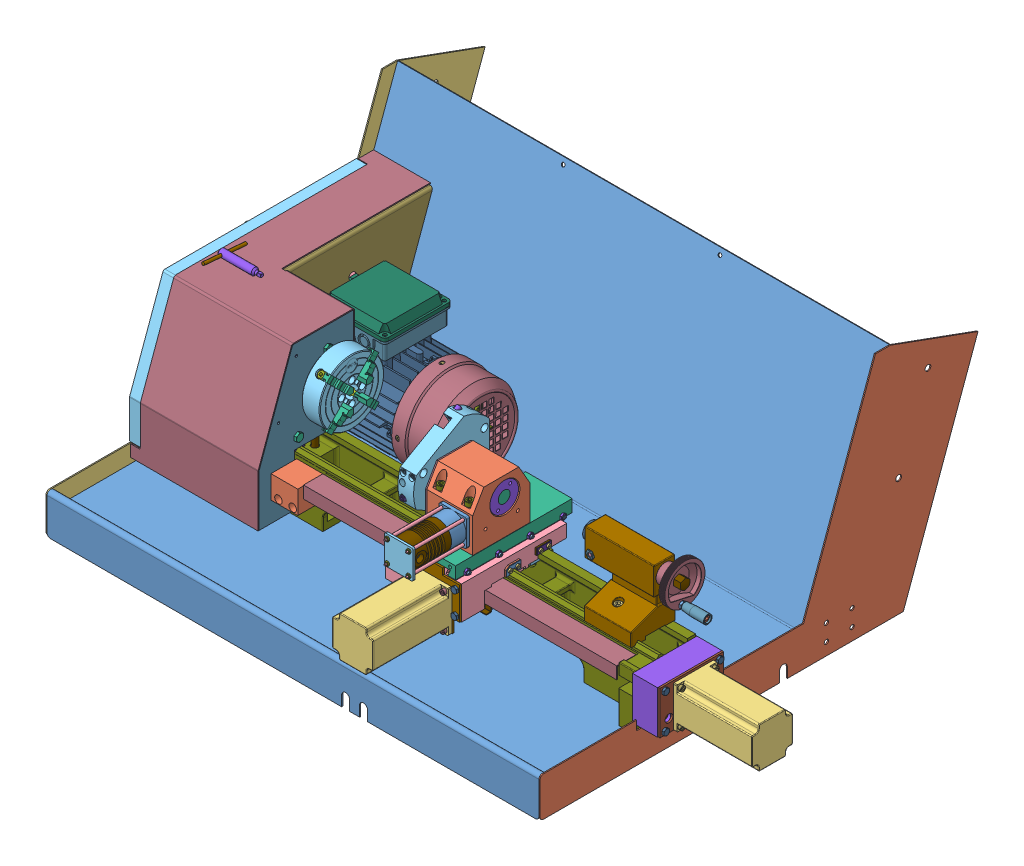
SolidWorks assembly Emco Compact 5 CNC, configuration Default. Lengths in mm.
Overall size (835.1 331.1 618.32).
327 component instances, 165 part files, 0 mates.
Components (placement in the parent):
- Emco Compact 5 CNC.stp-1: Emco Compact 5 CNC.stp [Default] at origin size (835.1 331.1 618.32)
  - A6A 060 001 chiptray.stp-1: A6A 060 001 chiptray.stp [Default] at origin size (690 331.1 611.82)
    - A6A 060 001 chiptray bottom part.stp-1: A6A 060 001 chiptray bottom part.stp [Default] at origin size (687 331.09 491)
    - A6A 060 001 chiptray right part.stp-1: A6A 060 001 chiptray right part.stp [Default] at (687 0 0) size (1.5 331.1 611.82)
    - A6A 060 001 chiptray left part.stp-1: A6A 060 001 chiptray left part.stp [Default] at (-1.5 0 0) size (1.5 331.1 611.82)
  - A6A 050 000 cover.stp-1: A6A 050 000 cover.stp [Default] at (0 55 -366.75) x (0 0 1) z (-1 0 0) size (316.79 204.5 24)
    - A6A 050 000 cover side.stp-1: A6A 050 000 cover side.stp [Default] at origin size (315.29 182 15)
    - A6A 050 000 cover strip.stp-1: A6A 050 000 cover strip.stp [Default] at (0 0 -13.5) size (316.79 183.5 15)
    - ZSR 12 0620 M6x20 Socket head screw.stp-1: ZSR 12 0620 M6x20 Socket head screw.stp [Default] at (82 176 3.1) x (0 0 -1) z (1 0 0) size (24 10 10)
    - ZSB 25 0640 M6 washer.stp-1: ZSB 25 0640 M6 washer.stp [Default] at (82 176 1.5) x (0 0 1) z (-1 0 0) size (1.6 12 12)
    - ZSB 25 0640 M6 washer.stp-2: ZSB 25 0640 M6 washer.stp [Default] at (82 176 -1.6) x (0 0 1) z (-1 0 0) size (1.6 12 12)
    - ZRG 71 0607 6mm retaining ring.stp-1: ZRG 71 0607 6mm retaining ring.stp [Default] at (82 173 -2.6) x (1 0 0) z (0 0 -1) size (7.95 9.79 0.7)
    - A6A 050 000 cover hinge_1.stp-1: A6A 050 000 cover hinge_1.stp [Default] at (233 0.5 1.5) x (0 -1 0) z (-1 0 0) size (23 6 44)
    - A6A 050 000 cover hinge_2.stp-1: A6A 050 000 cover hinge_2.stp [Default] at (189 0.5 1.5) x (0 1 0) z (1 0 0) size (23 6 44)
    - A6A 050 000 cover hinge shaft.stp-1: A6A 050 000 cover hinge shaft.stp [Default] at (189 0.5 1.5) x (0 0.845481 0.534005) z (1 0 0) size (3 3 44)
    - A6A 050 000 cover hinge_1.stp-2: A6A 050 000 cover hinge_1.stp [Default] at (53 0.5 1.5) x (0 -1 0) z (-1 0 0) size (23 6 44)
    - A6A 050 000 cover hinge_2.stp-2: A6A 050 000 cover hinge_2.stp [Default] at (9 0.5 1.5) x (0 1 0) z (1 0 0) size (23 6 44)
    - A6A 050 000 cover hinge shaft.stp-2: A6A 050 000 cover hinge shaft.stp [Default] at (9 0.5 1.5) x (0 0.845481 0.534005) z (1 0 0) size (3 3 44)
  - A6A 030 000 Headstock cover.stp-1: A6A 030 000 Headstock cover.stp [Default] at (66.5 30 -468.25) x (0 0 1) z (-1 0 0) size (339.29 210 178.5)
    - A6A 030 000 Headstock cover - Motorplate.stp-1: A6A 030 000 Headstock cover - Motorplate.stp [Default] at origin size (335.89 208.5 18.5)
    - A6A 030 000 Headstock cover - Topplate.stp-1: A6A 030 000 Headstock cover - Topplate.stp [Default] at (101.4998 25 -111.5) size (339.29 202.5 178.5)
    - A6A 030 000 Headstock cover - Spindleplate.stp-1: A6A 030 000 Headstock cover - Spindleplate.stp [Default] at (350 7.5 -110) x (0 0 -1) z (1 0 0) size (1.5 201 132)
    - A6A 030 000 Headstock cover - lock.stp-1: A6A 030 000 Headstock cover - lock.stp [Default] at (176.2113 208.5 35.5) x (0 0 1) z (1 0 0) size (21 13.5 12)
  - Bed complete.stp-1: Bed complete.stp [Default] at (86.5 30 -140.9) size (821.5 208.51 283.01)
    - Bed with head and tailstock.stp-1: Bed with head and tailstock.stp [Default] at origin size (594 187 111.85)
      - A6A 010 010 Bed.stp-1: A6A 010 010 Bed.stp [Default] at origin size (594 80 90)
      - A5A 010 020 Headstock.stp-1: A5A 010 020 Headstock.stp [Default] at (0 76.4996 -25.1) x (0 0 -1) z (1 0 0) size (80 110.5 90)
      - DIN 912 - M8 x 1,25 x 45 x 28.stp-1: DIN 912 - M8 x 1,25 x 45 x 28.stp [Default] at (17.5 50.5 -53.25) x (0 1 0) z (0 0 -1) size (53 13 13)
      - DIN 912 - M8 x 1,25 x 45 x 28.stp-2: DIN 912 - M8 x 1,25 x 45 x 28.stp [Default] at (80 50.5 -66.75) x (0 1 0) z (0 0 1) size (53 13 13)
      - DIN 912 - M8 x 1,25 x 45 x 28.stp-3: DIN 912 - M8 x 1,25 x 45 x 28.stp [Default] at (80 50.5 -45.25) x (0 1 0) z (0 0 1) size (53 13 13)
      - DIN 127 - A 8.stp-1: DIN 127 - A 8.stp [Default] at (80 52.5 -45.25) x (0 -1 0) z (0 0 -1) size (2 14.8 14.8)
      - DIN 127 - A 8.stp-2: DIN 127 - A 8.stp [Default] at (80 52.5 -66.75) x (0 -1 0) z (0 0 -1) size (2 14.8 14.8)
      - DIN 127 - A 8.stp-3: DIN 127 - A 8.stp [Default] at (17.5 52.5 -53.25) x (0 -1 0) z (0 0 1) size (2 14.8 14.8)
      - A6A 000 040 Bearing block.stp-1: A6A 000 040 Bearing block.stp [Default] at (92 36.5 -29.25) size (37.5 32 36)
      - DIN 912 - M5 x 0,8 x 30 x 22.stp-1: DIN 912 - M5 x 0,8 x 30 x 22.stp [Default] at (122.5 42.5 -5.25) x (0 0 -1) z (0 1 0) size (35 8.5 8.5)
      - DIN 912 - M5 x 0,8 x 30 x 22.stp-2: DIN 912 - M5 x 0,8 x 30 x 22.stp [Default] at (102.5 42.5 -5.25) x (0 0 -1) z (0 1 0) size (35 8.5 8.5)
      - eBom-prt21.stp-1: eBom-prt21.stp [Default] at origin
    - Mainspindle pulley.stp-1: Mainspindle pulley.stp [Default] at (-41.5 144.9996 -72.1) size (41.5 127.02 127.02)
      - A6A 000 020 pulley.stp-1: A6A 000 020 pulley.stp [Default] at (41 0 0) x (0 0.866396 -0.499357) z (0 0.499357 0.866396) size (93 41 93)
      - A6A 000 110 Dividing washer 100.stp-1: A6A 000 110 Dividing washer 100.stp [Default] at (25 0 0) x (0 -0.000742 1) z (-1 0 0) size (126 125.99 1)
      - ZSR 84 0516 M6x15 Flathead screw.stp-1: ZSR 84 0516 M6x15 Flathead screw.stp [Default] at (25 -23 -0.0171) x (-1 0 0) z (0 0 -1) size (19.3 8.5 8.5)
      - ZSR 84 0516 M6x15 Flathead screw.stp-2: ZSR 84 0516 M6x15 Flathead screw.stp [Default] at (25 11.5148 -19.91) x (-1 0 0) z (0 0.866025 0.5) size (19.3 8.5 8.5)
      - ZSR 84 0516 M6x15 Flathead screw.stp-3: ZSR 84 0516 M6x15 Flathead screw.stp [Default] at (25 11.4852 19.9271) x (-1 0 0) z (0 -0.866025 0.5) size (19.3 8.5 8.5)
      - A6A 000 240 Spacer.stp-1: A6A 000 240 Spacer.stp [Default] at (25 0 0) x (0 -1 0) z (0 0 1) size (36 16.5 36)
    - Slide assembly.stp-1: Slide assembly.stp [Default] at (280.3814 50 34.9) size (116 83.5 274.82)
      - ZME 200 260 - Cross slide spindle c..stp-1: ZME 200 260 - Cross slide spindle c..stp [Default] at (76.0442 55.2922 -13.5096) x (0 0 -1) z (-1 0 0) size (139.04 39.28 30.05)
        - DIN 625 SKF - SKF 608.stp-1: DIN 625 SKF - SKF 608.stp [Default] at (13.1404 13.5422 12.3565) x (0 -0.373068 -0.927804) z (1 0 0) size (22 22 7)
        - Bearing housing.stp-1: Bearing housing.stp [Default] at (6.4404 1.7922 24.8565) size (15.7 36 25)
        - Spindle.stp-1: Spindle.stp [Default] at (0.1404 13.5422 12.3565) size (125 9.5 9.5)
        - Upper nut.stp-1: Upper nut.stp [Default] at (127.1777 13.5422 12.3565) x (-1 0 0) z (0 0.926032 0.377445) size (23.5 18.99 19.4)
        - Nut housing.stp-1: Nut housing.stp [Default] at (119.6777 23.0422 -0.1435) x (0 0 1) z (1 0 0) size (25 23.65 40.5)
        - Lower nut.stp-1: Lower nut.stp [Default] at (77.1777 13.5422 12.3565) x (1 0 0) z (0 -0.105651 0.994403) size (23.5 17.5 17.5)
        - Spring.stp-1: Spring.stp [Default] at (103.1809 13.5422 12.3565) x (0 0.727516 0.686091) z (0 -0.686091 0.727516) size (18 1 18)
        - Spring.stp-2: Spring.stp [Default] at (101.1746 13.5422 12.3565) x (0 -0.17154 -0.985177) z (0 -0.985177 0.17154) size (18 1 18)
        - Spring.stp-3: Spring.stp [Default] at (100.6777 13.5422 12.3565) x (0 -0.908191 -0.418555) z (0 -0.418555 0.908191) size (18 1 18)
        - Spring.stp-4: Spring.stp [Default] at (103.6777 13.5422 12.3565) x (0 0.740638 -0.671905) z (0 0.671905 0.740638) size (18 1 18)
        - ISO 1207 - M3 x 10DIN EN ISO.stp-1: ISO 1207 - M3 x 10DIN EN ISO.stp [Default] at (124.1777 6.0422 4.3565) x (-1 0 0) z (0 0.872958 -0.487796) size (12 5.5 5.5)
        - Wheel.stp-1: Wheel.stp [Default] at (13.1404 13.5422 12.3565) x (0 -0.978803 -0.204804) z (0 0.204804 -0.978803) size (25.39 24.75 25.39)
        - DIN 916 - M5  x  12.stp-1: DIN 916 - M5  x  12.stp [Default] at (0.1404 13.5422 12.3565) x (-1 0 0) z (0 0.601717 -0.798709) size (12 5 5)
      - Stepmotor.stp-1: Stepmotor.stp [Default] at (1.7766 38.5507 -32.904) size (57 57 136.1)
        - Sprocket assy.stp-1: Sprocket assy.stp [Default] at (64.7234 -28.5507 9.304) x (1 0 0) z (0 -1 0) size (15.75 23.5 14.79)
          - Sprocket.stp-1: Sprocket.stp [Default] at origin size (10.01 23.5 10)
          - Washer.stp-1: Washer.stp [Default] at (0 6 0) x (1 0 0) z (0 1 0) size (14 14 0.5)
          - Washer.stp-2: Washer.stp [Default] at (0 21.5 0) x (1 0 0) z (0 -1 0) size (14 14 0.5)
          - DIN 471 - 8 x 0,8.stp-1: DIN 471 - 8 x 0,8.stp [Default] at (0 22.3 4) x (1 0 0) z (0 -1 0) size (10.25 12.45 0.8)
          - DIN 471 - 8 x 0,8.stp-2: DIN 471 - 8 x 0,8.stp [Default] at (-3.5618 5.2 -1.8203) x (0.455075 0 -0.890453) z (0 1 0) size (10.25 12.45 0.8)
        - DCNC_IP54_2NM_AP203.stp-1: DCNC_IP54_2NM_AP203.stp [Default] at origin size (57 57 130.6)
      - A6A 020  010 Slide.stp-1: A6A 020  010 Slide.stp [Default] at origin size (106 55.53 147)
      - A6A 020  080 Set screw M4x15.stp-1: A6A 020  080 Set screw M4x15.stp [Default] at (87.8963 51 -147.9373) x (0 -0.929398 -0.36908) z (0 -0.36908 0.929398) size (4 15 4)
      - A6A 020  080 Set screw M4x15.stp-2: A6A 020  080 Set screw M4x15.stp [Default] at (88.9997 51 -13.9373) x (0 0.202323 -0.979319) z (0 -0.979319 -0.202323) size (4 15 4)
      - A6A 020  080 Set screw M4x15.stp-3: A6A 020  080 Set screw M4x15.stp [Default] at (88.9997 51 -57.9373) x (0 -0.616904 -0.787038) z (0 -0.787038 0.616904) size (4 15 4)
      - A6A 020  080 Set screw M4x15.stp-4: A6A 020  080 Set screw M4x15.stp [Default] at (88.9997 51 -101.9373) x (0 -0.161487 -0.986875) z (0 -0.986875 0.161487) size (4 15 4)
      - A6A 020  020 Cross slide.stp-1: A6A 020  020 Cross slide.stp [Default] at (33.6877 48 -161.9373) x (0 0 1) z (-1 0 0) size (163 17 65)
      - A6A 020  070 Gib.stp-1: A6A 020  070 Gib.stp [Default] at (88.1021 56.1731 -162.3163) x (0 0 -1) z (-0.906308 0.422618 0) size (154 8 3)
      - ISO 4032 - M4ISO.stp-1: ISO 4032 - M4ISO.stp [Default] at (101.8877 51 -101.9373) x (-1 0 0) z (0 0 1) size (3.2 8.08 7)
      - ISO 4032 - M4ISO.stp-2: ISO 4032 - M4ISO.stp [Default] at (101.8877 51 -57.9373) x (-1 0 0) z (0 0 1) size (3.2 8.08 7)
      - ISO 4032 - M4ISO.stp-3: ISO 4032 - M4ISO.stp [Default] at (101.8877 51 -13.9373) x (-1 0 0) z (0 0 1) size (3.2 8.08 7)
      - ISO 4032 - M4ISO.stp-4: ISO 4032 - M4ISO.stp [Default] at (101.8877 51 -147.9373) x (-1 0 0) z (0 0 1) size (3.2 8.08 7)
      - A6A 000 070 Motor plate 1.stp-1: A6A 000 070 Motor plate 1.stp [Default] at (27 -18 0) x (0 0 1) z (-1 0 0) size (2.5 73 79)
      - ISO 4017 - M5 x 10DIN EN.stp-1: ISO 4017 - M5 x 10DIN EN.stp [Default] at (32 39 2.5) x (0 0 -1) z (0.991912 0.126928 0) size (13.5 9.24 8)
      - ISO 4017 - M5 x 10DIN EN.stp-2: ISO 4017 - M5 x 10DIN EN.stp [Default] at (101 39 2.5) x (0 0 -1) z (0.991912 0.126928 0) size (13.5 9.24 8)
      - ISO 4017 - M5 x 10DIN EN.stp-3: ISO 4017 - M5 x 10DIN EN.stp [Default] at (32 7 2.5) x (0 0 -1) z (0.991912 0.126928 0) size (13.5 9.24 8)
      - ISO 4017 - M5 x 10DIN EN.stp-4: ISO 4017 - M5 x 10DIN EN.stp [Default] at (101 7 2.5) x (0 0 -1) z (0.991912 0.126928 0) size (13.5 9.24 8)
      - DIN 912 - M5 x 0,8 x 8 x 6.stp-1: DIN 912 - M5 x 0,8 x 8 x 6.stp [Default] at (55.1877 59.3 -99.9373) x (0 -1 0) z (-0.992776 0 -0.119984) size (13 8.5 8.5)
      - DIN 912 - M5 x 0,8 x 8 x 6.stp-2: DIN 912 - M5 x 0,8 x 8 x 6.stp [Default] at (72.1877 59.3 -99.9373) x (0 -1 0) z (0.30564 0 0.952147) size (13 8.5 8.5)
      - DIN 912 - M5 x 0,8 x 10 x 8.stp-1: DIN 912 - M5 x 0,8 x 10 x 8.stp [Default] at (57.585 25.5 -25.65) x (0 0 -1) z (1 0 0) size (15 8.5 8.5)
      - DIN 912 - M5 x 0,8 x 10 x 8.stp-2: DIN 912 - M5 x 0,8 x 10 x 8.stp [Default] at (70.085 25.5 -25.65) x (0 0 -1) z (1 0 0) size (15 8.5 8.5)
      - ISO 4762 - M4 x 8ISO.stp-1: ISO 4762 - M4 x 8ISO.stp [Default] at (43 33.5 7.5) x (0 0 -1) z (0 1 0) size (12 7 7)
      - ISO 4762 - M4 x 8ISO.stp-2: ISO 4762 - M4 x 8ISO.stp [Default] at (43 -13.5 7.5) x (0 0 -1) z (0 1 0) size (12 7 7)
      - ISO 4762 - M4 x 8ISO.stp-3: ISO 4762 - M4 x 8ISO.stp [Default] at (90 33.5 7.5) x (0 0 -1) z (0 1 0) size (12 7 7)
      - ISO 4762 - M4 x 8ISO.stp-4: ISO 4762 - M4 x 8ISO.stp [Default] at (90 -13.5 7.5) x (0 0 -1) z (0 1 0) size (12 7 7)
      - DIN 913 - M6 x 6.stp-1: DIN 913 - M6 x 6.stp [Default] at (73.6877 59 -71.9373) x (0 1 0) z (0 0 1) size (6 6 6)
      - DIN 913 - M6 x 6.stp-2: DIN 913 - M6 x 6.stp [Default] at (73.6877 59 -88.9373) x (0 1 0) z (0 0 1) size (6 6 6)
      - DIN 913 - M6 x 6.stp-3: DIN 913 - M6 x 6.stp [Default] at (73.6877 59 -113.9373) x (0 1 0) z (0 0 1) size (6 6 6)
      - A6A 020  060 Cover sheet.stp-1: A6A 020  060 Cover sheet.stp [Default] at (45.335 44.5 -147.5) x (0 0 -1) z (1 0 0) size (45.5 11 37)
      - DIN 84 - M5 x 6.stp-1: DIN 84 - M5 x 6.stp [Default] at (50.335 50 -147.5) x (0 0 1) z (0.118737 0.992926 0) size (9.3 8.5 8.5)
      - DIN 84 - M5 x 6.stp-2: DIN 84 - M5 x 6.stp [Default] at (77.335 50 -147.5) x (0 0 1) z (-0.22668 -0.973969 0) size (9.3 8.5 8.5)
      - A6A 000 200 Wiper plate 1.stp-1: A6A 000 200 Wiper plate 1.stp [Default] at (30 31 -123) x (0 0 1) z (-1 0 0) size (20 8 1)
      - A6A 000 200 Wiper plate 1.stp-2: A6A 000 200 Wiper plate 1.stp [Default] at (108 31 -103) x (0 0 -1) z (1 0 0) size (20 8 1)
      - A6A 000 220 Felt wiper 1.stp-1: A6A 000 220 Felt wiper 1.stp [Default] at (32 31 -123) x (0 0 1) z (-1 0 0) size (20 9 2)
      - A6A 000 220 Felt wiper 1.stp-2: A6A 000 220 Felt wiper 1.stp [Default] at (106 31 -103) x (0 0 -1) z (1 0 0) size (20 9 2)
      - A6A 000 210 Wiper plate 2.stp-1: A6A 000 210 Wiper plate 2.stp [Default] at (-2 26.3 -80) x (0 0 1) z (-1 0 0) size (20 11 1)
      - A6A 000 210 Wiper plate 2.stp-2: A6A 000 210 Wiper plate 2.stp [Default] at (108 26 -60) x (0 0 -1) z (1 0 0) size (20 11 1)
      - A6A 000 230 Felt wiper 2.stp-1: A6A 000 230 Felt wiper 2.stp [Default] at (106 26 -60) x (0 0 -1) z (1 0 0) size (20 12 2)
      - A6A 000 230 Felt wiper 2.stp-2: A6A 000 230 Felt wiper 2.stp [Default] at (0 26.3 -80) x (0 0 1) z (-1 0 0) size (20 12 2)
      - DIN 84 - M3 x 8.stp-1: DIN 84 - M3 x 8.stp [Default] at (109 35 -107.5) x (-1 0 0) z (0 0 1) size (10 5.5 5.5)
      - DIN 84 - M3 x 8.stp-2: DIN 84 - M3 x 8.stp [Default] at (109 35 -118.5) x (-1 0 0) z (0 0 1) size (10 5.5 5.5)
      - DIN 84 - M3 x 8.stp-3: DIN 84 - M3 x 8.stp [Default] at (109 32 -75.5) x (-1 0 0) z (0 0 1) size (10 5.5 5.5)
      - DIN 84 - M3 x 8.stp-4: DIN 84 - M3 x 8.stp [Default] at (109 32 -64.5) x (-1 0 0) z (0 0 1) size (10 5.5 5.5)
      - DIN 84 - M3 x 8.stp-5: DIN 84 - M3 x 8.stp [Default] at (29 35 -118.5) size (10 5.5 5.5)
      - DIN 84 - M3 x 8.stp-6: DIN 84 - M3 x 8.stp [Default] at (29 35 -107.5) size (10 5.5 5.5)
      - DIN 84 - M3 x 8.stp-7: DIN 84 - M3 x 8.stp [Default] at (-3 32.3 -75.5) size (10 5.5 5.5)
      - DIN 84 - M3 x 8.stp-8: DIN 84 - M3 x 8.stp [Default] at (-3 32.3 -64.5) size (10 5.5 5.5)
      - A6A 000 050 Keep plate long.stp-1: A6A 000 050 Keep plate long.stp [Default] at (0 23 -86.8) x (0 -1 0) z (-1 0 0) size (3 13 106)
      - A6A 000 130 Keep plate short.stp-1: A6A 000 130 Keep plate short.stp [Default] at (32 20 -96.4) x (0 1 0) z (-1 0 0) size (3 13 74)
      - DIN 125 - A 5,3.stp-1: DIN 125 - A 5,3.stp [Default] at (101 20 -102.9) x (0 -1 0) z (0 0 1) size (1 10 10)
      - DIN 125 - A 5,3.stp-2: DIN 125 - A 5,3.stp [Default] at (69 20 -102.9) x (0 -1 0) z (0 0 1) size (1 10 10)
      - DIN 125 - A 5,3.stp-3: DIN 125 - A 5,3.stp [Default] at (37 20 -102.9) x (0 -1 0) z (0 0 1) size (1 10 10)
      - DIN 125 - A 5,3.stp-4: DIN 125 - A 5,3.stp [Default] at (101 20 -80.3) x (0 -1 0) z (0 0 1) size (1 10 10)
      - DIN 125 - A 5,3.stp-5: DIN 125 - A 5,3.stp [Default] at (69 20 -80.3) x (0 -1 0) z (0 0 1) size (1 10 10)
      - DIN 125 - A 5,3.stp-6: DIN 125 - A 5,3.stp [Default] at (5 20 -80.3) x (0 -1 0) z (0 0 1) size (1 10 10)
      - DIN 125 - A 5,3.stp-7: DIN 125 - A 5,3.stp [Default] at (37 20 -80.3) x (0 -1 0) z (0 0 1) size (1 10 10)
      - DIN 6912 - M5 x 12.stp-1: DIN 6912 - M5 x 12.stp [Default] at (101 19 -102.9) x (0 1 0) z (0 0 1) size (15.5 8.5 8.5)
      - DIN 6912 - M5 x 12.stp-2: DIN 6912 - M5 x 12.stp [Default] at (69 19 -80.3) x (0 1 0) z (0 0 1) size (15.5 8.5 8.5)
      - DIN 6912 - M5 x 12.stp-3: DIN 6912 - M5 x 12.stp [Default] at (69 19 -102.9) x (0 1 0) z (0 0 1) size (15.5 8.5 8.5)
      - DIN 6912 - M5 x 12.stp-4: DIN 6912 - M5 x 12.stp [Default] at (37 19 -102.9) x (0 1 0) z (0 0 1) size (15.5 8.5 8.5)
      - DIN 6912 - M5 x 12.stp-5: DIN 6912 - M5 x 12.stp [Default] at (37 19 -80.3) x (0 1 0) z (0 0 1) size (15.5 8.5 8.5)
      - DIN 6912 - M5 x 12.stp-6: DIN 6912 - M5 x 12.stp [Default] at (5 19 -80.3) x (0 1 0) z (0 0 1) size (15.5 8.5 8.5)
      - DIN 6912 - M5 x 12.stp-7: DIN 6912 - M5 x 12.stp [Default] at (101 19 -80.3) x (0 1 0) z (0 0 1) size (15.5 8.5 8.5)
    - ZME 200 270 - Lead screw complete.stp-1: ZME 200 270 - Lead screw complete.stp [Default] at (635.4404 14.7078 -61.3935) x (-1 0 0) z (0 0 -1) size (512.11 60 101.5)
      - DIN 625 SKF - SKF 608.stp-1: DIN 625 SKF - SKF 608.stp [Default] at (32.4404 41.7922 -47.1435) x (0 -0.373068 -0.927804) z (1 0 0) size (22 22 7)
      - Bearing housing Z.stp-1: Bearing housing Z.stp [Default] at (6.4404 1.7922 24.8565) size (35 60 90)
      - Spindle Z.stp-1: Spindle Z.stp [Default] at (19.4404 41.7922 -47.1435) x (1 0 0) z (0 0.197096 -0.980384) size (499.11 37.83 37.83)
      - Upper nut Z.stp-1: Upper nut Z.stp [Default] at (323.753 41.7922 -47.1435) x (-1 0 0) z (0 -0.996178 -0.087343) size (23.5 18.99 19.4)
      - Nut housing Z.stp-1: Nut housing Z.stp [Default] at (316.253 52.2922 -76.6435) x (0 0 1) z (1 0 0) size (40 26 50)
      - Lower nut Z.stp-1: Lower nut Z.stp [Default] at (263.753 41.7922 -47.1435) size (23.5 17.5 17.5)
      - Spring Z.stp-1: Spring Z.stp [Default] at (299.7562 41.7922 -47.1435) x (0 0.805867 0.592096) z (0 -0.592096 0.805867) size (18 1 18)
      - Spring Z.stp-2: Spring Z.stp [Default] at (297.7562 41.7922 -47.1435) x (0 0.078102 -0.996945) z (0 -0.996945 -0.078102) size (18 1 18)
      - Spring Z.stp-3: Spring Z.stp [Default] at (297.2593 41.7922 -47.1435) x (0 -0.953765 -0.300553) z (0 -0.300553 0.953765) size (18 1 18)
      - Spring Z.stp-4: Spring Z.stp [Default] at (300.253 41.7922 -47.1435) x (0 0.694828 -0.719176) z (0 0.719176 0.694828) size (18 1 18)
      - ISO 1207 - M3 x 10DIN EN ISO.stp-1: ISO 1207 - M3 x 10DIN EN ISO.stp [Default] at (320.753 34.2922 -55.1435) x (-1 0 0) z (0 0.826702 -0.56264) size (12 5.5 5.5)
      - Wheel Z.stp-1: Wheel Z.stp [Default] at (32.4404 41.7922 -47.1435) x (0 0.114782 -0.993391) z (0 0.993391 0.114782) size (25.39 24.75 25.39)
      - DIN 916 - M5  x  12.stp-1: DIN 916 - M5  x  12.stp [Default] at (19.4404 41.7922 -47.1435) x (-1 0 0) z (0 0.601717 -0.798709) size (12 5 5)
      - DIN 625 SKF - SKF 626-Z.stp-1: DIN 625 SKF - SKF 626-Z.stp [Default] at (514.4404 41.7922 -47.1435) x (0 0 1) z (-1 0 0) size (19 19 6)
      - DIN 471 - 6 x 0,7.stp-1: DIN 471 - 6 x 0,7.stp [Default] at (515.4404 44.7922 -47.1435) x (0 0 -1) z (1 0 0) size (7.95 9.79 0.7)
      - Washer-0.stp-1: Washer-0.stp [Default] at (515.4404 41.7922 -47.1435) x (0 -0.77803 -0.628227) z (0 0.628227 -0.77803) size (12 1 12)
      - A6A 040 000 Wiper sheet.stp-1: A6A 040 000 Wiper sheet.stp [Default] at (332.253 25.2922 -60.6435) x (-1 0 0) z (0 0 -1) size (82 19 25)
      - VeltPad.stp-1: VeltPad.stp [Default] at (324.253 28.2922 -53.1435) x (0 0 1) z (-1 0 0) size (4 16 8)
      - VeltPad.stp-2: VeltPad.stp [Default] at (250.253 28.2922 -53.1435) x (0 0 1) z (-1 0 0) size (4 16 8)
      - DIN 912 - M4 x 0,7 x 8 x 6,25.stp-1: DIN 912 - M4 x 0,7 x 8 x 6,25.stp [Default] at (271.253 25.2922 -54.6435) x (0 1 0) z (0 0 1) size (12 7 7)
      - DIN 912 - M4 x 0,7 x 8 x 6,25.stp-2: DIN 912 - M4 x 0,7 x 8 x 6,25.stp [Default] at (311.253 25.2922 -54.6435) x (0 1 0) z (0.945421 0 -0.325851) size (12 7 7)
    - Stepmotor.stp-1: Stepmotor.stp [Default] at (596.096 73.5507 20.4734) x (0 0 -1) z (1 0 0) size (57 57 136.1)
      - Sprocket assy.stp-1: Sprocket assy.stp [Default] at (64.7234 -28.5507 9.304) x (1 0 0) z (0 -1 0) size (15.75 23.5 14.79)
        - Sprocket.stp-1: Sprocket.stp [Default] at origin size (10.01 23.5 10)
        - Washer.stp-1: Washer.stp [Default] at (0 6 0) x (1 0 0) z (0 1 0) size (14 14 0.5)
        - Washer.stp-2: Washer.stp [Default] at (0 21.5 0) x (1 0 0) z (0 -1 0) size (14 14 0.5)
        - DIN 471 - 8 x 0,8.stp-1: DIN 471 - 8 x 0,8.stp [Default] at (0 22.3 4) x (1 0 0) z (0 -1 0) size (10.25 12.45 0.8)
        - DIN 471 - 8 x 0,8.stp-2: DIN 471 - 8 x 0,8.stp [Default] at (-3.5618 5.2 -1.8203) x (0.455075 0 -0.890453) z (0 1 0) size (10.25 12.45 0.8)
      - DCNC_IP54_2NM_AP203.stp-1: DCNC_IP54_2NM_AP203.stp [Default] at origin size (57 57 130.6)
    - DIN 472 - 55 x 2.stp-1: DIN 472 - 55 x 2.stp [Default] at (16.5 170.9996 -72.1) x (0 0 -1) z (1 0 0) size (58 56.27 2)
    - DIN 472 - 55 x 2.stp-2: DIN 472 - 55 x 2.stp [Default] at (74 164.7749 -55.2198) x (0 -0.649238 0.760585) z (-1 0 0) size (58 56.27 2)
    - A5A 000 010 main spindle.stp-1: A5A 000 010 main spindle.stp [Default] at (105 144.9996 -72.1) x (0 -0.999982 -0.005957) z (1 0 0) size (40 40 185)
    - SKF 2Z6006-2Z.stp-1: SKF 2Z6006-2Z.stp [Default] at (0 144.9996 -72.1) x (0 -0.839296 -0.543674) z (1 0 0) size (55 55 13)
    - SKF 2Z6006-2Z.stp-2: SKF 2Z6006-2Z.stp [Default] at (77 144.9996 -72.1) x (0 0.123416 -0.992355) z (1 0 0) size (55 55 13)
    - ZSB 10 5553 Supporting ring.stp-1: ZSB 10 5553 Supporting ring.stp [Default] at (16.5 144.9996 -72.1) x (0 0 1) z (-1 0 0) size (55 55 3)
    - ZSB 10 5553 Supporting ring.stp-2: ZSB 10 5553 Supporting ring.stp [Default] at (77 144.9996 -72.1) x (0 0 1) z (-1 0 0) size (55 55 3)
    - ZSB 02 6006 Compensating washer.stp-1: ZSB 02 6006 Compensating washer.stp [Default] at (10.5 144.9996 -72.1) x (0 -0.007521 -0.999972) z (1 0 0) size (55 57.25 3.02)
    - DIN 471 - 24 x 1,2(1).stp-1: DIN 471 - 24 x 1,2(1).stp [Default] at (-41.5 156.9996 -72.1) x (0 0 -1) z (1 0 0) size (28.5 30.84 1.2)
    - DIN 912 - M5 x 0,8 x 35 x 22.stp-1: DIN 912 - M5 x 0,8 x 35 x 22.stp [Default] at (621 33.5 -9.75) x (-1 0 0) z (0 0 1) size (40 8.5 8.5)
    - DIN 912 - M5 x 0,8 x 35 x 22.stp-2: DIN 912 - M5 x 0,8 x 35 x 22.stp [Default] at (621 45.5 -79.75) x (-1 0 0) z (0 0 1) size (40 8.5 8.5)
    - DIN 912 - M5 x 0,8 x 16 x 14.stp-1: DIN 912 - M5 x 0,8 x 16 x 14.stp [Default] at (364.1874 41 7.25) x (0 1 0) z (0 0 1) size (21 8.5 8.5)
    - DIN 912 - M5 x 0,8 x 16 x 14.stp-2: DIN 912 - M5 x 0,8 x 16 x 14.stp [Default] at (324.1874 41 7.25) x (0 1 0) z (0 0 1) size (21 8.5 8.5)
    - A6A 000 080 Motor plate 2.stp-1: A6A 000 080 Motor plate 2.stp [Default] at (629 16.5 -86.25) x (1 0 0) z (0 -1 0) size (2.5 89 60)
    - ISO 4762 - M4 x 8DIN EN ISO.stp-1: ISO 4762 - M4 x 8DIN EN ISO.stp [Default] at (636.5 68.5 -20.75) x (-1 0 0) z (0 0 1) size (12 7 7)
    - ISO 4762 - M4 x 8DIN EN ISO.stp-2: ISO 4762 - M4 x 8DIN EN ISO.stp [Default] at (636.5 21.5 -20.75) x (-1 0 0) z (0 0 1) size (12 7 7)
    - ISO 4762 - M4 x 8DIN EN ISO.stp-3: ISO 4762 - M4 x 8DIN EN ISO.stp [Default] at (636.5 68.5 -67.75) x (-1 0 0) z (0 0 1) size (12 7 7)
    - ISO 4762 - M4 x 8DIN EN ISO.stp-4: ISO 4762 - M4 x 8DIN EN ISO.stp [Default] at (636.5 21.5 -67.75) x (-1 0 0) z (0 0 1) size (12 7 7)
    - ISO 4017 - M5 x 10DIN EN.stp-1: ISO 4017 - M5 x 10DIN EN.stp [Default] at (631.5 22 -79.25) x (-1 0 0) z (0 0 1) size (13.5 9.24 8)
    - ISO 4017 - M5 x 10DIN EN.stp-2: ISO 4017 - M5 x 10DIN EN.stp [Default] at (631.5 22 -3.25) x (-1 0 0) z (0 0 1) size (13.5 9.24 8)
    - ISO 4017 - M5 x 10DIN EN.stp-3: ISO 4017 - M5 x 10DIN EN.stp [Default] at (631.5 71 -79.25) x (-1 0 0) z (0 0 1) size (13.5 9.24 8)
    - ISO 4017 - M5 x 10DIN EN.stp-4: ISO 4017 - M5 x 10DIN EN.stp [Default] at (631.5 71 -3.25) x (-1 0 0) z (0 0 1) size (13.5 9.24 8)
    - A6A 000 060 Cover.stp-1: A6A 000 060 Cover.stp [Default] at (130 53 -0.75) size (437.5 30 27)
    - DIN 963 - M4 x 8.stp-1: DIN 963 - M4 x 8.stp [Default] at (280 48 -25.75) x (0 0 -1) z (1 0 0) size (8 7.5 7.43)
    - DIN 963 - M4 x 8.stp-2: DIN 963 - M4 x 8.stp [Default] at (510 48 -25.75) x (0 0 -1) z (1 0 0) size (8 7.5 7.43)
    - DIN 963 - M4 x 8.stp-3: DIN 963 - M4 x 8.stp [Default] at (405 48 -25.75) x (0 0 -1) z (1 0 0) size (8 7.5 7.43)
    - DIN 963 - M4 x 8.stp-4: DIN 963 - M4 x 8.stp [Default] at (145 48 -25.75) x (0 0 -1) z (0.225143 0.974326 0) size (8 7.5 7.43)
  - Coutershaft pulley with Carrier plate.stp-1: Coutershaft pulley with Carrier plate.stp [Default] at (81.5 51.372 -387.4209) x (0 -0.031919 0.99949) z (-1 0 0) size (223.31 179.81 60)
    - A6A 130 000 Carrier plate.stp-1: A6A 130 000 Carrier plate.stp [Default] at origin size (185 130 4)
    - A5A 060 XXX Washer for countershaft pulley.stp-1: A5A 060 XXX Washer for countershaft pulley.stp [Default] at (25.5 116 4) size (20 20 3)
    - ZSB 12 1203 Shim ring.stp-1: ZSB 12 1203 Shim ring.stp [Default] at (25.5 116 7.3) x (1 0 0) z (0 0 -1) size (18 18 0.3)
    - ZSB 10 2181 Supporting ring.stp-1: ZSB 10 2181 Supporting ring.stp [Default] at (25.5 116 39.1) size (18 18 1.2)
    - A5A 060 XXX Shaft for countershaft pulley.stp-1: A5A 060 XXX Shaft for countershaft pulley.stp [Default] at (25.5 116 -13) x (1 0 0) z (0 -1 0) size (12 60 12)
    - DIN 6799 - 9 10.stp-1: DIN 6799 - 9 10.stp [Default] at (27.6465 120.4896 40.3) x (0.902188 -0.431343 0) z (0 0 1) size (18.8 15.36 1.1)
    - A5A 060 xxx Countershaft pulley bearing.stp-1: A5A 060 xxx Countershaft pulley bearing.stp [Default] at (25.5 116 30.8) size (17 17 8)
    - A5A 060 xxx Countershaft pulley bearing.stp-2: A5A 060 xxx Countershaft pulley bearing.stp [Default] at (25.5 116 15.3) x (1 0 0) z (0 0 -1) size (17 17 8)
    - A5A 060 000 Countershaft pulley.stp-1: A5A 060 000 Countershaft pulley.stp [Default] at (25.5 116 5.8) x (-0.942772 -0.333437 0) z (-0.333437 0.942772 0) size (100 33 100)
  - 200 420 independent chuck.stp-1: 200 420 independent chuck.stp [Default] at (187.5 174.9996 -213) x (0 0.005957 -0.999982) z (1 0 0) size (90 90 36.75)
    - A5Z 420 010 Housing.stp-1: A5Z 420 010 Housing.stp [Default] at origin size (90 90 25.4)
    - A5Z 420 020 Revisible jaw.stp-1: A5Z 420 020 Revisible jaw.stp [Default] at (-30.1313 36.4952 14.75) x (-0.707107 -0.707107 0) z (0 0 1) size (9.03 34 22)
    - A2Z 420 020 Spindle.stp-1: A2Z 420 020 Spindle.stp [Default] at (-14.9285 14.9285 12.7) x (0.689607 0.689607 0.221096) z (-0.156339 -0.156339 0.975252) size (12 22 12)
    - A5Z 420 020 Revisible jaw.stp-2: A5Z 420 020 Revisible jaw.stp [Default] at (-36.4952 -30.1313 14.75) x (0.707107 -0.707107 0) z (0 0 1) size (9.03 34 22)
    - A2Z 420 020 Spindle.stp-2: A2Z 420 020 Spindle.stp [Default] at (-14.9285 -14.9285 12.7) x (-0.689607 0.689607 0.221096) z (0.156339 -0.156339 0.975252) size (12 22 12)
    - A5Z 420 020 Revisible jaw.stp-3: A5Z 420 020 Revisible jaw.stp [Default] at (30.1313 -36.4952 14.75) x (0.707107 0.707107 0) z (0 0 1) size (9.03 34 22)
    - A2Z 420 020 Spindle.stp-3: A2Z 420 020 Spindle.stp [Default] at (14.9285 -14.9285 12.7) x (-0.689607 -0.689607 0.221096) z (0.156339 0.156339 0.975252) size (12 22 12)
    - A5Z 420 020 Revisible jaw.stp-4: A5Z 420 020 Revisible jaw.stp [Default] at (36.4952 30.1313 14.75) x (-0.707107 0.707107 0) z (0 0 1) size (9.03 34 22)
    - A2Z 420 020 Spindle.stp-4: A2Z 420 020 Spindle.stp [Default] at (14.9285 14.9285 12.7) x (0.689607 -0.689607 0.221096) z (-0.156339 0.156339 0.975252) size (12 22 12)
  - Key assy.stp-1: Key assy.stp [Default] at (79.3627 245 -221.0139) x (0 -0.996195 0.087156) z (0 -0.087156 -0.996195) size (10 58 61)
    - A2Z 420 040 Key.stp-1: A2Z 420 040 Key.stp [Default] at origin size (10 58 10.01)
    - ZST 75 0460 Toggle.stp-1: ZST 75 0460 Toggle.stp [Default] at (0 53 -30) size (4 4 61)
  - MS63_B14.stp-1: MS63_B14.stp [Default] at (162 95.9366 -327.6259) x (0 0 1) z (-1 0 0) size (124.64 169.78 221.01)
    - Gehuse_MS63.stp-1: Gehuse_MS63.stp [Default] at (-0.1035 0.303 0) size (119 121.5 118)
    - B14-Flansch_MS63.stp-1: B14-Flansch_MS63.stp [Default] at (-0.1035 0.303 60.5319) size (119 119 48.01)
    - B-Lagerschild_MS63.stp-1: B-Lagerschild_MS63.stp [Default] at (-0.1035 0.303 -56.5319) x (-1 0 0) z (0 0 -1) size (118.99 118.99 43)
    - Lfterhaube_MS63.stp-1: Lfterhaube_MS63.stp [Default] at (-0.1035 0.303 -77.2372) x (-0.999871 -0.016068 0) z (0 0 -1) size (122.6 122.6 64.6)
    - Klemmnkastenunterteil_MS63.stp-1: Klemmnkastenunterteil_MS63.stp [Default] at (-0.1035 77.803 18) x (1 0 0) z (0 0 -1) size (94 35 94)
    - Klemmenkastendeckel_MS63.stp-1: Klemmenkastendeckel_MS63.stp [Default] at (-0.1035 100.303 18) x (-1 0 0) z (0 0 1) size (94 15 94)
    - Lfterflgel_MS63.stp-1: Lfterflgel_MS63.stp [Default] at (-0.1035 0.303 -90.5) x (0.708442 -0.705769 0) z (0 0 -1) size (83 86.37 22)
  - 260 040 Turret toolpost.stp-1: 260 040 Turret toolpost.stp [Default] at (401.0691 145 -209.4373) size (89.5 120.57 175.5)
    - ZED 21 3074 Compression spring.stp-1: ZED 21 3074 Compression spring.stp [Default] at (8.0384 22.2391 59.2521) x (0.9925 0 0.122247) z (0.122247 0 -0.9925) size (5.97 7.19 5.94)
      - Compress Spring1.stp-1: Compress Spring1.stp [Default] at (-2.8144 -5.0599 0) size (5.97 7.19 5.94)
        - Compress Spring11.stp-1: Compress Spring11.stp [Default] at origin size (5.97 7.19 5.94)
    - A6Z 046 000 Motor complete.stp-1: A6Z 046 000 Motor complete.stp [Default] at (40.5 26.5 105) x (0 1 0) z (1 0 0) size (38 99 38.04)
      - A6Z 046 Housing.stp-1: A6Z 046 Housing.stp [Default] at origin size (38 52 38.04)
      - A6Z 046 Gear 60-1.stp-1: A6Z 046 Gear 60-1.stp [Default] at (-19 -20.5 -19) x (1 0 0) z (0 -1 0) size (38 38 79)
    - A6Z 040 040 Housing.stp-1: A6Z 040 040 Housing.stp [Default] at origin size (64 75 80)
    - A6Z 040 110 Bush.stp-1: A6Z 040 110 Bush.stp [Default] at (34 26.5 80) x (0.546692 0.837333 0) z (-0.837333 0.546692 0) size (20 29 20)
    - DIN 916 - M6  x  8.stp-1: DIN 916 - M6  x  8.stp [Default] at (34 17.5 65) x (0 -1 0) z (0.896157 0 0.443737) size (8 6 6)
    - A6Z 040 020 Toolpost disc.stp-1: A6Z 040 020 Toolpost disc.stp [Default] at (-25.5 48 35) x (0 -1 0) z (1 0 0) size (118.2 106 22.5)
    - A6Z 040 030 Shaft.stp-1: A6Z 040 030 Shaft.stp [Default] at (-8 48 35) x (1 0 0) z (0 0.866025 -0.5) size (71 40 39.88)
    - DIN 625 SKF - SKF 6004-2Z.stp-1: DIN 625 SKF - SKF 6004-2Z.stp [Default] at (22 48 35) x (0 -0.311827 0.950139) z (-1 0 0) size (42 42 12)
    - DIN 625 SKF - SKF 6004-2Z.stp-2: DIN 625 SKF - SKF 6004-2Z.stp [Default] at (47 48 35) x (0 -0.491177 -0.87106) z (1 0 0) size (42 42 12)
    - A6Z 040 100 Nut.stp-1: A6Z 040 100 Nut.stp [Default] at (63 48 35) x (0 -0.821516 0.570185) z (-1 0 0) size (40 40 4)
    - DIN 6885 - A 4 x 4 x 16.stp-1: DIN 6885 - A 4 x 4 x 16.stp [Default] at (24.5 43.25 26.7728) x (1 0 0) z (0 0.5 0.866025) size (16 4 4)
    - A6Z 040 060 Worm wheel.stp-1: A6Z 040 060 Worm wheel.stp [Default] at (34 48 35) x (0 -0.866025 0.5) z (-1 0 0) size (33 32.98 24)
    - DIN 912 - M6 x 1 x 20 x 17,5.stp-1: DIN 912 - M6 x 1 x 20 x 17,5.stp [Default] at (-17 42 24.6077) x (1 0 0) z (0 -0.981488 -0.191522) size (26 10 10)
    - DIN 912 - M6 x 1 x 20 x 17,5.stp-2: DIN 912 - M6 x 1 x 20 x 17,5.stp [Default] at (-17 42 45.3923) x (1 0 0) z (0 -0.981488 -0.191522) size (26 10 10)
    - DIN 912 - M6 x 1 x 20 x 17,5.stp-3: DIN 912 - M6 x 1 x 20 x 17,5.stp [Default] at (-17 60 35) x (1 0 0) z (0 -0.981488 -0.191522) size (26 10 10)
    - ZSB 02 6004 Compensating washer.stp-1: ZSB 02 6004 Compensating washer.stp [Default] at (46 48 35) x (0 0.384912 -0.922953) z (1 0 0) size (42.01 43.94 3.05)
    - A6Z 040 080 Seal plate.stp-1: A6Z 040 080 Seal plate.stp [Default] at (0 0.75 0.75) x (0 0 1) z (-1 0 0) size (79 74 2)
    - A6Z 040 120 Leaf spring.stp-1: A6Z 040 120 Leaf spring.stp [Default] at (0.5 28 68) size (8 1.5 33)
    - A6Z 040 190 Set screw.stp-1: A6Z 040 190 Set screw.stp [Default] at (4.5 29.5 59) x (1 0 0) z (0 0 -1) size (6 16 6)
    - DIN 963 - M4 x 6.stp-1: DIN 963 - M4 x 6.stp [Default] at (-1.7 66 64) x (1 0 0) z (0 0.522282 -0.852773) size (6 7.5 7.43)
    - DIN 963 - M4 x 6.stp-2: DIN 963 - M4 x 6.stp [Default] at (-1.7 66 16) x (1 0 0) z (0 0 1) size (6 7.5 7.43)
    - DIN 963 - M4 x 6.stp-3: DIN 963 - M4 x 6.stp [Default] at (-1.7 15 11.5) size (6 7.5 7.43)
    - DIN 963 - M4 x 6.stp-4: DIN 963 - M4 x 6.stp [Default] at (-1.7 15 68.5) x (1 0 0) z (0 -0.000006 1) size (6 7.5 7.43)
    - A6Z 040 050 Worm.stp-1: A6Z 040 050 Worm.stp [Default] at (34 26.5 57) x (0 0 1) z (-0.825667 -0.564158 0) size (70 15 15)
    - DIN 625 SKF - SKF 6000-2Z.stp-1: DIN 625 SKF - SKF 6000-2Z.stp [Default] at (34 26.5 9) x (-0.736805 -0.676106 0) z (0 0 1) size (26 26 8)
    - ISO 10511 - M8.stp-1: ISO 10511 - M8.stp [Default] at (34 26.5 9) x (0 0 -1) z (0.238328 0.971185 0) size (6.86 15.01 13)
    - ZBU 50 0015 Bearing bush.stp-1: ZBU 50 0015 Bearing bush.stp [Default] at (34 26.5 51) x (0.567803 0.823165 0) z (0 0 1) size (14 14 10)
    - A6Z 040 070 Cover.stp-1: A6Z 040 070 Cover.stp [Default] at (34 26.5 -2) x (0 0 1) z (-0.866025 0.5 0) size (11 42 42)
    - DIN 963 - M4 x 8.stp-1: DIN 963 - M4 x 8.stp [Default] at (42 12.6436 -2.2) x (0 0 1) z (-0.995762 -0.091963 0) size (8 7.5 7.43)
    - DIN 963 - M4 x 8.stp-2: DIN 963 - M4 x 8.stp [Default] at (42 40.3564 -2.2) x (0 0 1) z (-0.998704 -0.0509 0) size (8 7.5 7.43)
    - DIN 963 - M4 x 8.stp-3: DIN 963 - M4 x 8.stp [Default] at (18 26.5 -2.2) x (0 0 1) z (-0.997744 -0.067134 0) size (8 7.5 7.43)
    - A6Z 040 160 Bolt.stp-1: A6Z 040 160 Bolt.stp [Default] at (55.5 41.5 164.5) x (-0.120379 0.992728 0) z (0 0 -1) size (4 4 88)
    - A6Z 040 160 Bolt.stp-2: A6Z 040 160 Bolt.stp [Default] at (25.5 11.5 76.5) x (0.812434 -0.583054 0) z (0 0 1) size (4 4 88)
    - A6Z 040 160 Bolt.stp-3: A6Z 040 160 Bolt.stp [Default] at (25.5 41.5 164.5) x (-0.065192 -0.997873 0) z (0 0 -1) size (4 4 88)
    - A6Z 040 160 Bolt.stp-4: A6Z 040 160 Bolt.stp [Default] at (55.5 11.5 164.5) x (-0.9944 -0.105682 0) z (0 0 -1) size (4 4 88)
    - A6Z 040 170 Cover.stp-1: A6Z 040 170 Cover.stp [Default] at (20.5 46.5 155) size (40 40 5)
    - ISO 8752 - 2 x 10  (1) DIN EN ISO.stp-1: ISO 8752 - 2 x 10  (1) DIN EN ISO.stp [Default] at (29 26.5 69) size (10 2 1.99)
    - DIN 934 - M3 x 0,5.stp-1: DIN 934 - M3 x 0,5.stp [Default] at (25.5 41.5 162.4) x (0 0 -1) z (0 1 0) size (2.4 6.35 5.5)
    - DIN 934 - M3 x 0,5.stp-2: DIN 934 - M3 x 0,5.stp [Default] at (55.5 41.5 162.4) x (0 0 -1) z (0 1 0) size (2.4 6.35 5.5)
    - DIN 934 - M3 x 0,5.stp-3: DIN 934 - M3 x 0,5.stp [Default] at (25.5 11.5 162.4) x (0 0 -1) z (0 1 0) size (2.4 6.35 5.5)
    - DIN 934 - M3 x 0,5.stp-4: DIN 934 - M3 x 0,5.stp [Default] at (55.5 11.5 162.4) x (0 0 -1) z (0 1 0) size (2.4 6.35 5.5)
    - DIN 913 - M6 x 6.stp-1: DIN 913 - M6 x 6.stp [Default] at (-20.5 65.8155 85.0864) x (0 -0.14396 0.989584) z (0 0.989584 0.14396) size (6 6 6)
    - DIN 913 - M6 x 6.stp-2: DIN 913 - M6 x 6.stp [Default] at (-8.5 65.8155 85.0864) x (0 -0.14396 0.989584) z (0 0.989584 0.14396) size (6 6 6)
    - DIN 913 - M6 x 16.stp-1: DIN 913 - M6 x 16.stp [Default] at (-19.5 27.8555 82.1086) x (0 0.5 0.866025) z (0 -0.866025 0.5) size (16 6 6)
    - DIN 913 - M6 x 16.stp-2: DIN 913 - M6 x 16.stp [Default] at (-19.5 41.8788 74.0122) x (0 0.5 0.866025) z (0 -0.866025 0.5) size (16 6 6)
    - DIN 913 - M6 x 6.stp-3: DIN 913 - M6 x 6.stp [Default] at (-20.5 -4.2839 25.3854) x (0 -0.785024 -0.619465) z (0 -0.619465 0.785024) size (6 6 6)
    - DIN 913 - M6 x 6.stp-4: DIN 913 - M6 x 6.stp [Default] at (-8.5 -4.2839 25.3854) x (0 -0.785024 -0.619465) z (0 -0.619465 0.785024) size (6 6 6)
    - DIN 913 - M6 x 16.stp-3: DIN 913 - M6 x 16.stp [Default] at (-19.5 17.275 -6) x (0 -1 0) z (0 0 -1) size (16 6 6)
    - DIN 913 - M6 x 16.stp-4: DIN 913 - M6 x 16.stp [Default] at (-19.5 17.275 10.1928) x (0 -1 0) z (0 0 -1) size (16 6 6)
    - DIN 913 - M6 x 6.stp-5: DIN 913 - M6 x 6.stp [Default] at (-20.5 82.4684 -5.4719) x (0 0.928984 -0.370119) z (0 -0.370119 -0.928984) size (6 6 6)
    - DIN 913 - M6 x 6.stp-6: DIN 913 - M6 x 6.stp [Default] at (-8.5 82.4684 -5.4719) x (0 0.928984 -0.370119) z (0 -0.370119 -0.928984) size (6 6 6)
    - DIN 913 - M6 x 16.stp-5: DIN 913 - M6 x 16.stp [Default] at (-19.5 98.8695 28.8914) x (0 0.5 -0.866025) z (0 0.866025 0.5) size (16 6 6)
    - DIN 913 - M6 x 16.stp-6: DIN 913 - M6 x 16.stp [Default] at (-19.5 84.8462 20.795) x (0 0.5 -0.866025) z (0 0.866025 0.5) size (16 6 6)
  - Tailstock barret.stp-1: Tailstock barret.stp [Default] at (552.4146 107 -166.5) size (169.3 113.68 80.18)
    - A5A 010 030 Tailstock housing.stp-1: A5A 010 030 Tailstock housing.stp [Default] at origin size (97 83 61)
    - A5A 121 000 Barret metric.stp-1: A5A 121 000 Barret metric.stp [Default] at (89.2 68 -46.5) x (-1 0 0) z (0 0 -1) size (96 22.01 22.01)
    - A5A 120 030 Lead screw.stp-1: A5A 120 030 Lead screw.stp [Default] at (122.2 68 -46.5) x (-1 0 0) z (0 0.938328 -0.345747) size (78 12 12)
    - A5A 120 020 Bearing bush.stp-1: A5A 120 020 Bearing bush.stp [Default] at (79.7 68 -46.5) x (1 0 0) z (0 -0.389576 -0.920994) size (17.8 22 22)
    - A5A 022 000 Hand wheel.stp-1: A5A 022 000 Hand wheel.stp [Default] at (97.5 68 -46.5) x (1 0 0) z (0 -0.215542 -0.976495) size (28 56.5 56.5)
    - A5A 021 050 Handle.stp-1: A5A 021 050 Handle.stp [Default] at (129.5 46.273 -41.7042) x (1 0 0) z (0 0.256362 0.966581) size (33 12 12)
    - A3A 000 040 Clamping plate.stp-1: A3A 000 040 Clamping plate.stp [Default] at (48 -10 -50) x (0 0 -1) z (1 0 0) size (37 6 20)
    - DIN 915 - M6 x 20.stp-1: DIN 915 - M6 x 20.stp [Default] at (42.5 59 -46.5) x (0 -1 0) z (0.001281 0 0.999999) size (20 6 6)
    - DIN 914 - M6 x 20.stp-1: DIN 914 - M6 x 20.stp [Default] at (85.5 59 -46.5) x (0 -1 0) z (0.001281 0 0.999999) size (20 6 6)
    - DIN 917 - M8 x 1,25 13.stp-1: DIN 917 - M8 x 1,25 13.stp [Default] at (115.5 68 -46.5) x (1 0 0) z (0 -0.60872 -0.793385) size (12.1 13 15.01)
    - DIN 934 - M5 x 0,8.stp-1: DIN 934 - M5 x 0,8.stp [Default] at (129.5 46.273 -41.7042) x (-1 0 0) z (0 0 -1) size (4 9.24 8)
    - DIN 934 - M5 x 0,8.stp-2: DIN 934 - M5 x 0,8.stp [Default] at (120.5 46.273 -41.7042) x (-1 0 0) z (0 0.674912 0.737898) size (4 9.24 8)
    - DIN 912 - M5 x 0,8 x 40 x 22.stp-1: DIN 912 - M5 x 0,8 x 40 x 22.stp [Default] at (155.5 46.273 -41.7042) x (-1 0 0) z (0 0 -1) size (45 8.5 8.5)
    - DIN 912 - M6 x 1 x 30 x 27,5.stp-1: DIN 912 - M6 x 1 x 30 x 27,5.stp [Default] at (58 18 -21) x (0 -1 0) z (0 0 1) size (36 10 10)
    - DIN 912 - M6 x 1 x 25 x 22,5.stp-1: DIN 912 - M6 x 1 x 25 x 22,5.stp [Default] at (7.5 52 -57) x (0 0 1) z (-1 0 0) size (31 10 10)
    - DIN 934 - M6 x 1.stp-1: DIN 934 - M6 x 1.stp [Default] at (7.5 52 -36) x (0 0 1) z (0.866025 -0.5 0) size (5.08 11.55 10)
  - DIN 933 - M6  x 12.stp-1: DIN 933 - M6  x 12.stp [Default] at (178 210.9996 -213) x (-1 0 0) z (0 0 -1) size (16 11.55 10)
  - DIN 933 - M6  x 12.stp-2: DIN 933 - M6  x 12.stp [Default] at (178 124.9996 -171.5) x (-1 0 0) z (0 0 -1) size (16 11.55 10)
  - ISO 7049 - ST3,5 x 9,5 - C - ZDIN ISO.stp-1: ISO 7049 - ST3,5 x 9,5 - C - ZDIN ISO.stp [Default] at (-1.5 42 -346.75) size (12.05 7 7)
  - ISO 7049 - ST3,5 x 9,5 - C - ZDIN ISO.stp-2: ISO 7049 - ST3,5 x 9,5 - C - ZDIN ISO.stp [Default] at (-1.5 42 -324.75) size (12.05 7 7)
  - ISO 7049 - ST3,5 x 9,5 - C - ZDIN ISO.stp-3: ISO 7049 - ST3,5 x 9,5 - C - ZDIN ISO.stp [Default] at (-1.5 42 -166.75) size (12.05 7 7)
  - ISO 7049 - ST3,5 x 9,5 - C - ZDIN ISO.stp-4: ISO 7049 - ST3,5 x 9,5 - C - ZDIN ISO.stp [Default] at (-1.5 42 -144.75) size (12.05 7 7)
  - DIN 6912 - M6 x 16.stp-1: DIN 6912 - M6 x 16.stp [Default] at (72.5 33.1 -140) x (0 -1 0) z (0 0 1) size (20 10 10)
  - DIN 6912 - M6 x 16.stp-2: DIN 6912 - M6 x 16.stp [Default] at (72.5 33.1 -360) x (0 -1 0) z (0 0 1) size (20 10 10)
  - DIN 125 - A 6,4.stp-1: DIN 125 - A 6,4.stp [Default] at (72.5 31.5 -360) x (0 1 0) z (0 0 -1) size (1.6 12 12)
  - DIN 125 - A 6,4.stp-2: DIN 125 - A 6,4.stp [Default] at (72.5 33.1 -140) x (0 -1 0) z (0 0 1) size (1.6 12 12)
  - DIN 9021 - 6,4.stp-1: DIN 9021 - 6,4.stp [Default] at (72.5 28.5 -140) x (0 -1 0) z (0 0 1) size (1.6 18 18)
  - DIN 9021 - 6,4.stp-2: DIN 9021 - 6,4.stp [Default] at (72.5 28.5 -360) x (0 -1 0) z (0 0 1) size (1.6 18 18)
  - DIN 934 - M6 x 1.stp-1: DIN 934 - M6 x 1.stp [Default] at (72.5 21.9 -360) x (0 1 0) z (0 0 1) size (5.08 11.55 10)
  - DIN 934 - M6 x 1.stp-2: DIN 934 - M6 x 1.stp [Default] at (72.5 21.9 -140) x (0 1 0) z (0 0 1) size (5.08 11.55 10)
  - DIN 603 - M8 x 20.stp-1: DIN 603 - M8 x 20.stp [Default] at (202.5 28.5 -197.5) x (0 1 0) z (-1 0 0) size (24.88 20.65 20.65)
  - DIN 603 - M8 x 20.stp-2: DIN 603 - M8 x 20.stp [Default] at (652.5 28.5 -197.5) x (0 1 0) z (-1 0 0) size (24.88 20.65 20.65)
  - DIN 9021 - 8,4.stp-1: DIN 9021 - 8,4.stp [Default] at (652.5 39 -197.5) x (0 1 0) z (0 0 1) size (2 24 24)
  - DIN 9021 - 8,4.stp-2: DIN 9021 - 8,4.stp [Default] at (202.5 39 -197.5) x (0 1 0) z (0 0 1) size (2 24 24)
  - DIN 934 - M8 x 1,25.stp-1: DIN 934 - M8 x 1,25.stp [Default] at (202.5 47.5 -197.5) x (0 -1 0) z (0 0 1) size (6.52 15.01 13)
  - DIN 934 - M8 x 1,25.stp-2: DIN 934 - M8 x 1,25.stp [Default] at (652.5 47.5 -197.5) x (0 -1 0) z (0 0 1) size (6.52 15.01 13)
  - DIN 933 - M6  x 12.stp-3: DIN 933 - M6  x 12.stp [Default] at (83.5 210.9996 -213) size (16 11.55 10)
  - DIN 933 - M6  x 12.stp-4: DIN 933 - M6  x 12.stp [Default] at (83.5 124.9996 -171.5) size (16 11.55 10)
  - A5A 000 100 Bearing shaft.stp-1: A5A 000 100 Bearing shaft.stp [Default] at (98.5 65 -218.9) x (0 1 0) z (0 0 1) size (10 34 10)
  - DIN 9021 - 8,4.stp-3: DIN 9021 - 8,4.stp [Default] at (77.5 65 -218.9) x (-1 0 0) z (0 0 1) size (2 24 24)
  - ISO 4033 - M8ISO.stp-1: ISO 4033 - M8ISO.stp [Default] at (68 65 -218.9) size (7.7 15.01 13)
  - DIN 934 - M8 x 1,25.stp-3: DIN 934 - M8 x 1,25.stp [Default] at (93.5 166.499 -358.2313) x (-1 0 0) z (0 0.732354 0.680924) size (6.52 15.01 13)
  - DIN 9021 - 8,4.stp-4: DIN 9021 - 8,4.stp [Default] at (85 166.499 -358.2313) x (1 0 0) z (0 -0.033688 -0.999432) size (2 24 24)
  - DIN 912 - M6 x 1 x 60 x 24.stp-1: DIN 912 - M6 x 1 x 60 x 24.stp [Default] at (453.0691 197 -136.9373) x (0 -1 0) z (0 0 1) size (66 10 10)
  - DIN 912 - M6 x 1 x 60 x 24.stp-2: DIN 912 - M6 x 1 x 60 x 24.stp [Default] at (453.0691 197 -201.9373) x (0 -1 0) z (0 0 1) size (66 10 10)
  - DIN 912 - M6 x 1 x 60 x 24.stp-3: DIN 912 - M6 x 1 x 60 x 24.stp [Default] at (413.0691 197 -201.9373) x (0 -1 0) z (0 0 1) size (66 10 10)
  - DIN 912 - M6 x 1 x 60 x 24.stp-4: DIN 912 - M6 x 1 x 60 x 24.stp [Default] at (413.0691 197 -136.9373) x (0 -1 0) z (0 0 1) size (66 10 10)
  - A5A 000 030 Motor pulley.stp-1: A5A 000 030 Motor pulley.stp [Default] at (81.5 96.2396 -327.7295) x (-1 0 0) z (0 1 0) size (38.5 59 59)
  - DIN 9021 - 5,3.stp-1: DIN 9021 - 5,3.stp [Default] at (55.8 96.2396 -327.7295) x (1 0 0) z (0 -0.989155 0.146875) size (1.2 15 15)
  - DIN 9021 - 4,3.stp-1: DIN 9021 - 4,3.stp [Default] at (54.8 96.2396 -327.7295) x (1 0 0) z (0 -0.989155 0.146875) size (1 12 12)
  - DIN 84 - M4 x 12.stp-1: DIN 84 - M4 x 12.stp [Default] at (54.8 96.2396 -327.7295) x (1 0 0) z (0 -0.989155 0.146875) size (14.6 7 7)
